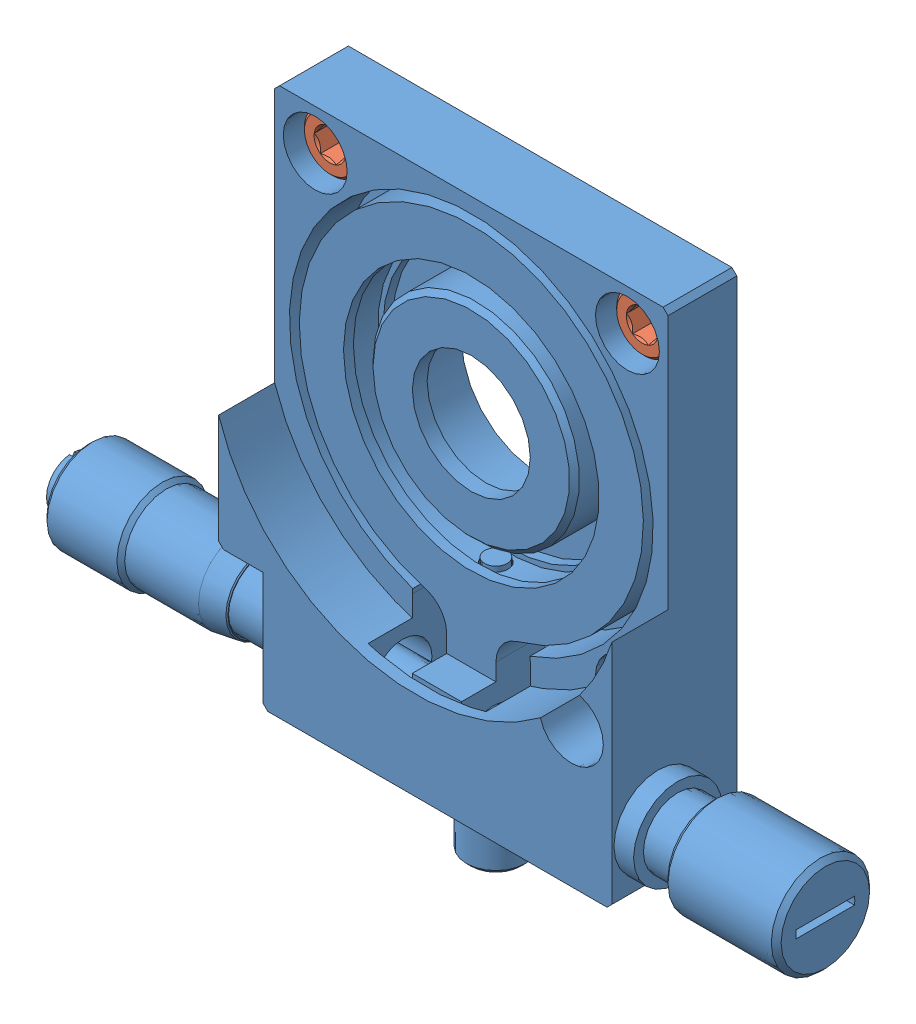
SolidWorks assembly stage_124-0030_with_bolts, configuration Default. Lengths in mm.
Overall size (78.17 59 15.91).
4 component instances, 2 part files, 6 mates.
Components (placement in the parent):
- stage_124-0030-1: stage_124-0030 [Default] at (3.2024 51.9087 67.2127) size (78.17 59 13)
- 6-32_L=0.19inch-1: 6-32_L=0.19inch [93235A142] at (-12.6726 67.7837 64.4502) x (-0.923728 -0.383049 0) z (0 0 -1) size (5.74 5.74 8.58)
- 6-32_L=0.19inch-2: 6-32_L=0.19inch [93235A142] at (19.0774 67.7837 64.4502) x (-0.923728 -0.383049 0) z (0 0 -1) size (5.74 5.74 8.58)
- 6-32_L=0.19inch-3: 6-32_L=0.19inch [93235A142] at (19.0774 36.0337 64.4502) x (-0.923728 -0.383049 0) z (0 0 -1) size (5.74 5.74 8.58)
Mates (geometry in assembly coordinates):
- Coincident1: coincident aligned: plane of 6-32_L=0.19inch-2 through (19.0774 67.7837 69.2127) normal (0 0 -1); plane of 6-32_L=0.19inch-3 through (19.0774 36.0337 69.2127) normal (0 0 -1)
- Coincident2: coincident aligned: plane of 6-32_L=0.19inch-1 through (-12.6726 67.7837 69.2127) normal (0 0 -1); plane of 6-32_L=0.19inch-2 through (19.0774 67.7837 69.2127) normal (0 0 -1)
- Coincident3: coincident anti-aligned: plane of stage_124-0030-1 through (-12.6726 67.7837 69.2127) normal (0 0 1); plane of 6-32_L=0.19inch-1 through (-12.6726 67.7837 69.2127) normal (0 0 -1)
- Concentric1: concentric anti-aligned: circle of stage_124-0030-1; circle of 6-32_L=0.19inch-1
- Concentric2: concentric aligned: circle of stage_124-0030-1; circle of 6-32_L=0.19inch-2
- Concentric3: concentric anti-aligned: circle of stage_124-0030-1; circle of 6-32_L=0.19inch-3
